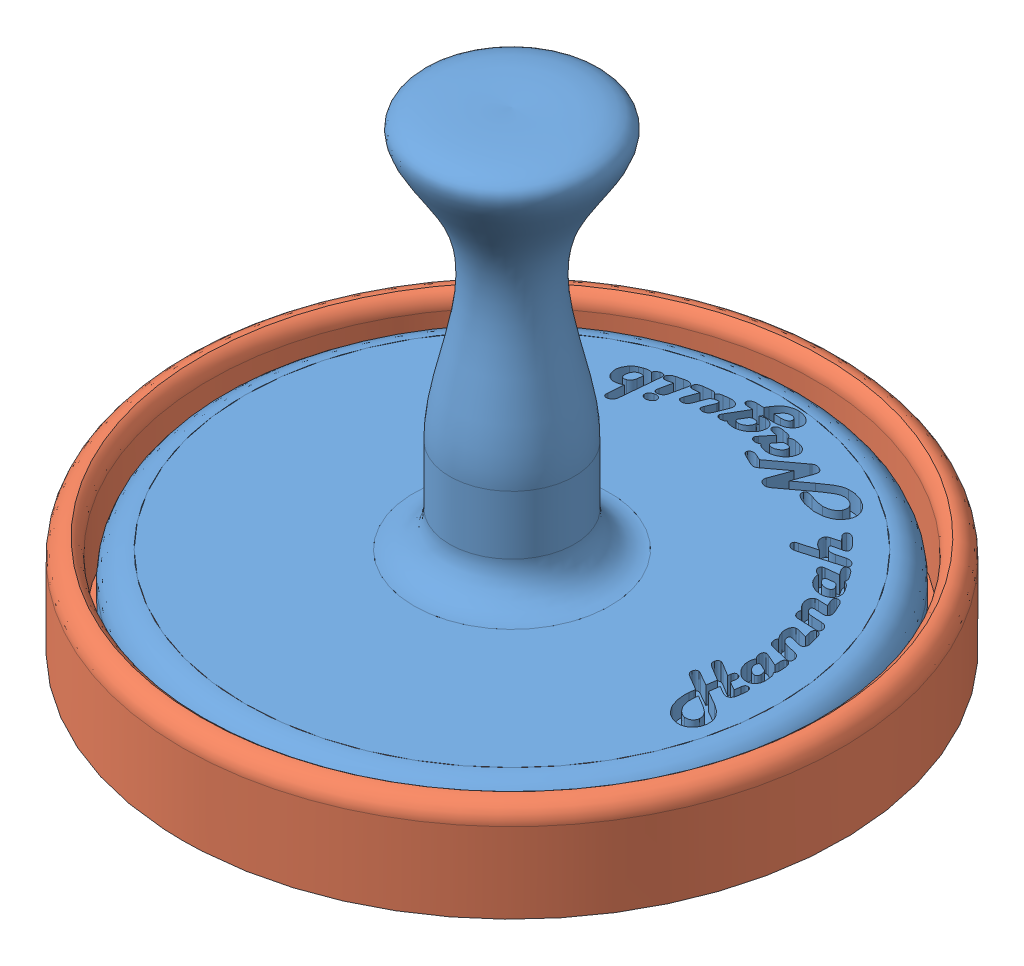
SolidWorks assembly Assem1, configuration Default. Lengths in mm.
Overall size (93.98 68.71 93.98).
2 component instances, 2 part files, 2 mates.
Components (placement in the parent):
- Stamp_Hannah-2: Stamp_Hannah [Default] at (55.7677 29.1249 38.7865) size (83.82 66.43 83.82)
- StampCap_Hannah-2: StampCap_Hannah [Default] at (55.7677 26.8389 38.7865) size (93.98 13.97 93.98)
Mates (geometry in assembly coordinates):
- Coincident5: coincident: plane of Stamp_Hannah-2 through (55.7677 29.1249 38.7865) normal (0 -1 0); plane of StampCap_Hannah-2 through (55.7677 29.1249 38.7865) normal (0 1 0)
- Concentric2: concentric anti-aligned: cylinder of Stamp_Hannah-2 through (55.7677 39.2849 38.7865) axis (0 -1 0) radius 41.91; cylinder of StampCap_Hannah-2 through (55.7677 29.1249 38.7865) axis (0 1 0) radius 43.18
